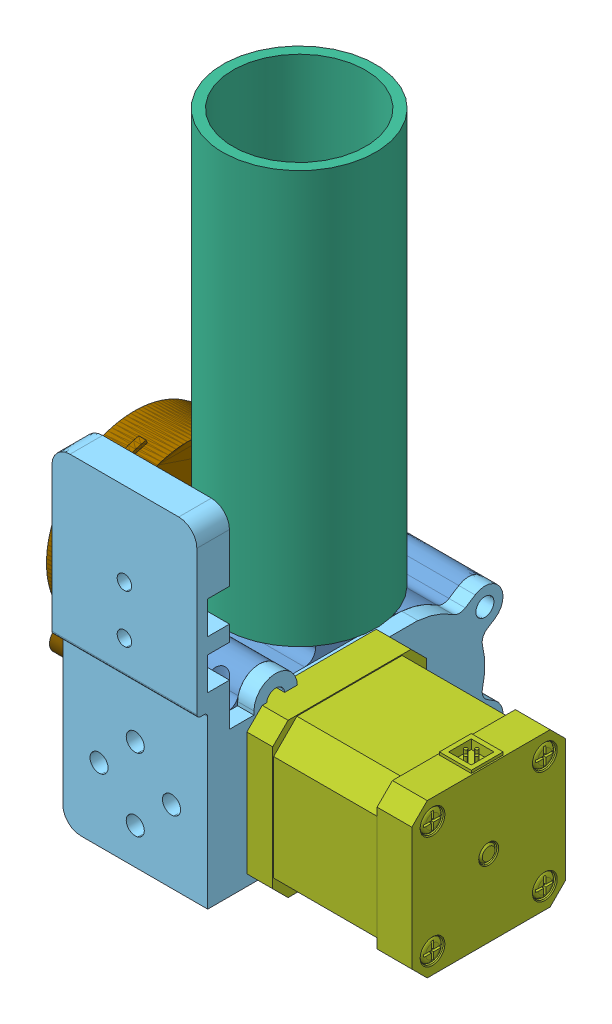
SolidWorks assembly Extruder_Assembly, configuration Default. Lengths in mm.
Overall size (107.18 167.79 84.5).
17 component instances, 11 part files, 42 mates.
Components (placement in the parent):
- body_newgearpump-1: body_newgearpump [Default] at (14.5 0 -44.25) x (0 0 1) z (-1 0 0) size (74.75 55 22)
- Gear_key_newgearpump-1: Gear_key_newgearpump [Default] at (-7.25 0 -32) x (0 -0.975447 -0.220236) z (1 0 0) size (30 28.68 14.75)
- Gear_newgearpump-1: Gear_newgearpump [Default] at (-7.5 -0.0531 -56.5847) x (0 0.602161 -0.798375) z (1 0 0) size (30 28.68 15)
- cover_newgearpump-1: cover_newgearpump [Default] at (-7.5 0 -44.25) x (0 0 1) z (-1 0 0) size (74.75 55 6.35)
- Extruder_mount_IDEA2-1: Extruder_mount_IDEA2 [Default] at (-1 0 0) size (40 100.75 84.5)
- vat_newgearpump-1: vat_newgearpump [Default] at (0 26 -44.25) x (0.996863 0 0.079144) z (-0.079144 0 0.996863) size (42.16 123.95 42.16)
- M5x6-1: M5x6 [Default] at (-18.85 -14 -76.5) size (11 8.5 8.5) (hidden)
- M5x6-2: M5x6 [Default] at (-18.85 -22 -26.75) size (11 8.5 8.5) (hidden)
- M5x6-3: M5x6 [Default] at (-18.85 14 -76.5) size (11 8.5 8.5) (hidden)
- M5x6-4: M5x6 [Default] at (-11 0 -9.5) x (0 0 1) z (-1 0 0) size (11 8.5 8.5) (hidden)
- M5x6-5: M5x6 [Default] at (-1 -10 -9.5) x (0 0 1) z (-1 0 0) size (11 8.5 8.5) (hidden)
- M5x6-6: M5x6 [Default] at (-1 10 -9.5) x (0 0 1) z (-1 0 0) size (11 8.5 8.5) (hidden)
- DC_Steppers-1: DC_Steppers [6627T91] at (27.519 0 -32) x (0 0 1) z (-1 0 0) size (42.4 43.16 74.07)
- M5x6-7: M5x6 [Default] at (-18.85 21 -18.75) size (11 8.5 8.5) (hidden)
- 5015_Lightweight_Duct_Standard_Left-1: 5015_Lightweight_Duct_Standard_Left [Default] at (-42.5064 11.5 -59.1358) x (0 -1 0) z (1 0 0) size (71.89 40.5 26.6)
- fan_5015-blower-2: fan_5015-blower [Default] at (-25.5064 316 841.5392) x (0 -1 0) z (-1 0 0) size (51.27 52.75 14.7)
- fan_mount-1: fan_mount [Default] at (-13.85 -1.8833 -45.6235) x (0 0 1) z (0 -1 0) size (46.53 6.5 38)
Mates (geometry in assembly coordinates):
- Coincident113: coincident anti-aligned: plane of Extruder_mount_IDEA2-1 through (14.5 20 -58) normal (-1 0 0); plane of body_newgearpump-1 through (14.5 -22 -26.75) normal (1 0 0)
- Concentric7: concentric aligned: cylinder of Extruder_mount_IDEA2-1 through (65.2952 14 -76.5) axis (-1 0 0) radius 2.5; cylinder of body_newgearpump-1 through (14.5 14 -76.5) axis (-1 0 0) radius 2.5
- Concentric8: concentric aligned: cylinder of Extruder_mount_IDEA2-1 through (65.2952 -14 -76.5) axis (-1 0 0) radius 2.5; cylinder of body_newgearpump-1 through (14.5 -14 -76.5) axis (-1 0 0) radius 2.5
- Concentric9: concentric anti-aligned: cylinder of body_newgearpump-1 through (14.5 0 -32) axis (-1 0 0) radius 2.5; cylinder of Gear_key_newgearpump-1 through (-7.25 0 -32) axis (1 0 0) radius 2.49
- Coincident114: coincident anti-aligned: plane of body_newgearpump-1 through (7.5 0 -32) normal (-1 0 0); plane of Gear_key_newgearpump-1 through (7.5 0 -32) normal (1 0 0)
- Coincident115: coincident anti-aligned: plane of body_newgearpump-1 through (7.5 0 -32) normal (-1 0 0); plane of Gear_newgearpump-1 through (7.5 -0.0531 -56.5847) normal (1 0 0)
- Tangent11: tangent aligned: cylinder of body_newgearpump-1 through (7.5 0 -56.5) axis (-1 0 0) radius 15.1; cylinder of Gear_newgearpump-1 through (7.5 -0.0531 -56.5847) axis (-1 0 0) radius 15
- Coincident116: coincident anti-aligned: plane of body_newgearpump-1 through (-7.5 -22 -26.75) normal (-1 0 0); plane of cover_newgearpump-1 through (-7.5 -22 -26.75) normal (1 0 0)
- Concentric10: concentric aligned: cylinder of body_newgearpump-1 through (14.5 14 -76.5) axis (-1 0 0) radius 2.5; cylinder of cover_newgearpump-1 through (-7.5 14 -76.5) axis (-1 0 0) radius 2.5
- Concentric11: concentric aligned: cylinder of body_newgearpump-1 through (-7.5 21 -18.75) axis (1 0 0) radius 2.5; cylinder of cover_newgearpump-1 through (-13.85 21 -18.75) axis (1 0 0) radius 2.5
- Concentric16: concentric aligned: circle of body_newgearpump-1; circle of vat_newgearpump-1
- Coincident121: coincident anti-aligned: plane of body_newgearpump-1 through (14.5 26 -44.25) normal (0 1 0); plane of vat_newgearpump-1 through (0 26 -44.25) normal (0 -1 0)
- Coincident122: coincident anti-aligned: plane of body_newgearpump-1 through (14.5 -22 -26.75) normal (1 0 0); plane of DC_Steppers-1 through (14.5 0 -32) normal (-1 0 0)
- Tangent10: tangent anti-aligned: cylinder of Gear_key_newgearpump-1 through (-7.25 -9.6875 -38.3843) axis (1 0 0) radius 6; cylinder of Gear_newgearpump-1 through (-7.5 -9.8585 -50.3831) axis (1 0 0) radius 6
- Coincident117: coincident anti-aligned: plane of cover_newgearpump-1 through (-13.85 -22 -26.75) normal (-1 0 0); plane of M5x6-7 through (-13.85 23.488 -18.75) normal (1 0 0)
- Concentric12: concentric anti-aligned: cylinder of cover_newgearpump-1 through (-13.85 21 -18.75) axis (1 0 0) radius 2.5; cylinder of M5x6-7 through (-107.5555 21 -18.75) axis (-1 0 0) radius 4.25
- Coincident118: coincident anti-aligned: plane of cover_newgearpump-1 through (-13.85 -22 -26.75) normal (-1 0 0); plane of M5x6-3 through (-13.85 16.488 -76.5) normal (1 0 0)
- Concentric13: concentric aligned: cylinder of cover_newgearpump-1 through (-7.5 14 -76.5) axis (-1 0 0) radius 2.5; cylinder of M5x6-3 through (-107.5555 14 -76.5) axis (-1 0 0) radius 4.25
- Coincident119: coincident anti-aligned: plane of cover_newgearpump-1 through (-13.85 -22 -26.75) normal (-1 0 0); plane of M5x6-2 through (-13.85 -19.512 -26.75) normal (1 0 0)
- Concentric14: concentric anti-aligned: cylinder of cover_newgearpump-1 through (-13.85 -22 -26.75) axis (1 0 0) radius 2.5; cylinder of M5x6-2 through (-107.5555 -22 -26.75) axis (-1 0 0) radius 4.25
- Coincident120: coincident anti-aligned: plane of cover_newgearpump-1 through (-13.85 -22 -26.75) normal (-1 0 0); plane of M5x6-1 through (-13.85 -11.512 -76.5) normal (1 0 0)
- Concentric15: concentric aligned: cylinder of cover_newgearpump-1 through (-7.5 -14 -76.5) axis (-1 0 0) radius 2.5; cylinder of M5x6-1 through (-107.5555 -14 -76.5) axis (-1 0 0) radius 4.25
- Concentric4: concentric aligned: cylinder of Extruder_mount_IDEA2-1 through (-1 10 -4.5) axis (0 0 -1) radius 4.5; cylinder of M5x6-6 through (-1 10 -98.2055) axis (0 0 -1) radius 4.25
- Coincident110: coincident anti-aligned: plane of Extruder_mount_IDEA2-1 through (-1 10 -4.5) normal (0 0 -1); plane of M5x6-6 through (-1 12.488 -4.5) normal (0 0 1)
- Concentric5: concentric aligned: cylinder of Extruder_mount_IDEA2-1 through (-1 -10 -4.5) axis (0 0 -1) radius 4.5; cylinder of M5x6-5 through (-1 -10 -98.2055) axis (0 0 -1) radius 4.25
- Coincident111: coincident anti-aligned: plane of Extruder_mount_IDEA2-1 through (-1 -10 -4.5) normal (0 0 -1); plane of M5x6-5 through (-1 -7.512 -4.5) normal (0 0 1)
- Concentric6: concentric aligned: cylinder of Extruder_mount_IDEA2-1 through (-11 0 -4.5) axis (0 0 -1) radius 4.5; cylinder of M5x6-4 through (-11 0 -98.2055) axis (0 0 -1) radius 4.25
- Coincident112: coincident anti-aligned: plane of Extruder_mount_IDEA2-1 through (-11 0 -4.5) normal (0 0 -1); plane of M5x6-4 through (-11 2.488 -4.5) normal (0 0 1)
- Concentric17: concentric anti-aligned: cylinder of Extruder_mount_IDEA2-1 through (19.001 0 -32) axis (-1 0 0) radius 12.5732; cylinder of DC_Steppers-1 through (-9.5 0 -32) axis (1 0 0) radius 2.25
- Distance11: distance = 17 mm anti-aligned: plane of 5015_Lightweight_Duct_Standard_Left-1 through (-42.5064 11.5 -59.1358) normal (1 0 0); plane of fan_5015-blower-2 through (-25.5064 316 841.5392) normal (-1 0 0)
- Distance8: distance = 304.5 mm aligned: plane of 5015_Lightweight_Duct_Standard_Left-1 through (-42.5064 11.5 -59.1358) normal (0 -1 0); plane of fan_5015-blower-2 through (-25.5064 316 841.5392) normal (0 -1 0)
- Distance10: distance = 900.675 mm anti-aligned: plane of fan_5015-blower-2 through (-25.5064 316 841.5392) normal (0 0 1); plane of 5015_Lightweight_Duct_Standard_Left-1 through (-42.5064 11.5 -59.1358) normal (0 0 -1)
- Distance20: distance = 11.5 mm anti-aligned: plane of 5015_Lightweight_Duct_Standard_Left-1 through (-42.5064 11.5 -59.1358) normal (0 -1 0)
- Distance15: distance = 100 mm: plane of assembly through (0 0 0) normal (1 0 0); plane of 5015_Lightweight_Duct_Standard_Left-1 through (-42.5064 11.5 -59.1358) normal (1 0 0); plane of assembly
- Coincident146: coincident aligned: plane of Extruder_mount_IDEA2-1 through (-1 0 0) normal (0 0 1)
- Coincident147: coincident aligned: plane of Extruder_mount_IDEA2-1 through (-1 0 0) normal (0 1 0)
- Distance16: distance = 1 mm aligned: plane of Extruder_mount_IDEA2-1 through (-1 0 0) normal (1 0 0)
- Parallel19: parallel anti-aligned: plane of 5015_Lightweight_Duct_Standard_Left-1 through (-42.5064 11.5 -59.1358) normal (0 0 -1)
- Parallel21: parallel aligned: plane of 5015_Lightweight_Duct_Standard_Left-1 through (-42.5064 11.5 -59.1358) normal (1 0 0)
- Distance19: distance = 16 mm: point of 5015_Lightweight_Duct_Standard_Left-1
- Coincident156: coincident: plane of fan_mount-1 through (-13.85 -1.8833 -45.6235) normal (1 0 0); plane of cover_newgearpump-1 through (-13.85 -22 -26.75) normal (-1 0 0)
- Parallel23: parallel anti-aligned: plane of fan_mount-1 through (-13.85 -1.8833 -45.6235) normal (0 -1 0)
